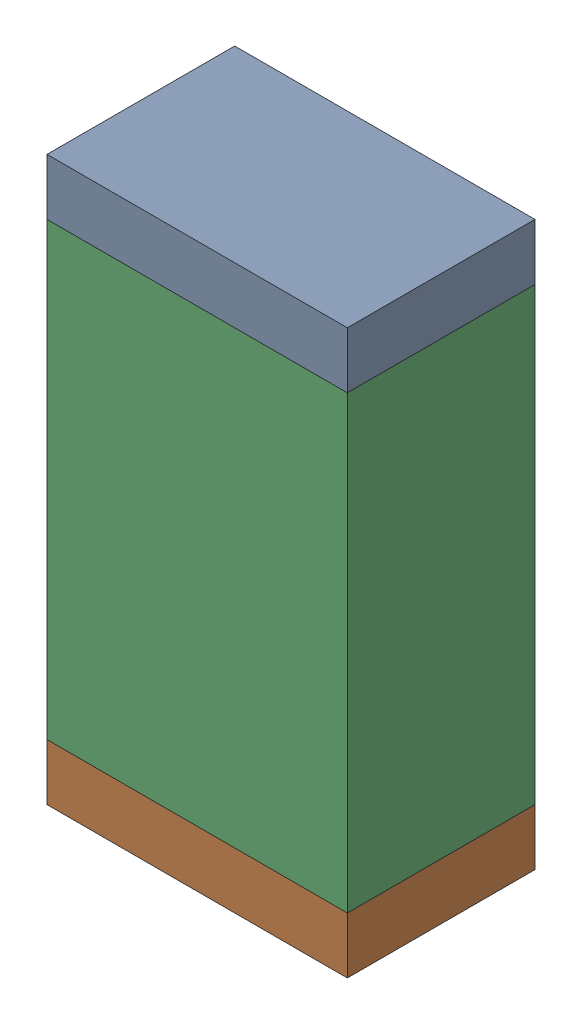
SolidWorks assembly D1, configuration Default. Lengths in mm.
Overall size (0.8 1.5 0.5).
6 component instances, 2 part files, 0 mates.
Components (placement in the parent):
- 810156592-1: 810156592 [Default] at (119.45 8.975 0) size (0.8 0.15 0.5)
  - Extruded_7-1: Extruded_7 [Default] at origin size (0.8 0.15 0.5)
- 810156592-2: 810156592 [Default] at (119.45 7.625 0) size (0.8 0.15 0.5)
  - Extruded_7-1: Extruded_7 [Default] at origin size (0.8 0.15 0.5)
- 810156976-1: 810156976 [Default] at (119.45 8.3 0) size (0.8 1.2 0.5)
  - Extruded_6-1: Extruded_6 [Default] at origin size (0.8 1.2 0.5)
